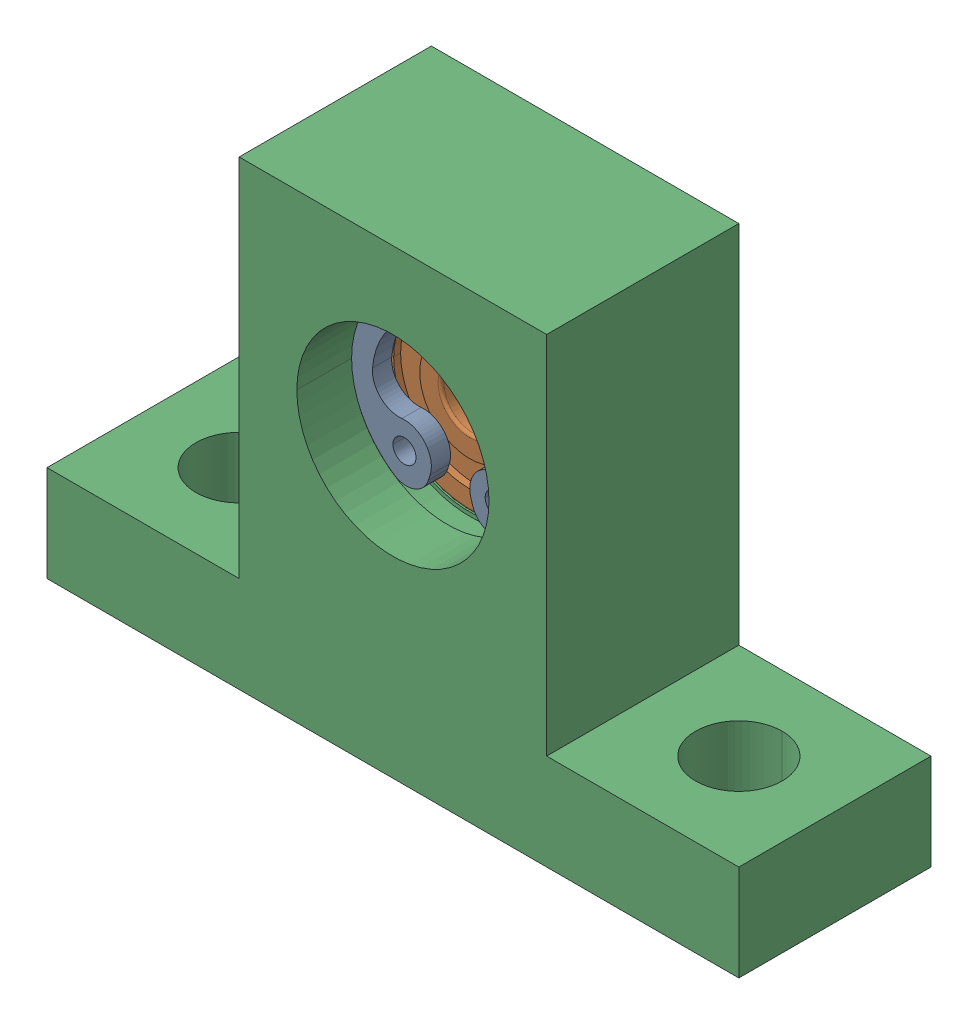
SolidWorks assembly BGHKB623ZZ_15, configuration Default. Lengths in mm.
Overall size (36 24 10).
3 component instances, 3 part files, 0 mates.
Components (placement in the parent):
- BGHKB623ZZ_15_3-1: BGHKB623ZZ_15_3 [Default] at (0 0 1.5) x (0 0 1) z (-1 0 0) size (1 9.68 10.4)
- BGHKB623ZZ_15_5-1: BGHKB623ZZ_15_5 [Default] at (0 0 -3) x (0 0 1) z (-1 0 0) size (4 10 10)
- BGHKB623ZZ_15_7-1: BGHKB623ZZ_15_7 [Default] at origin size (36 24 10)
